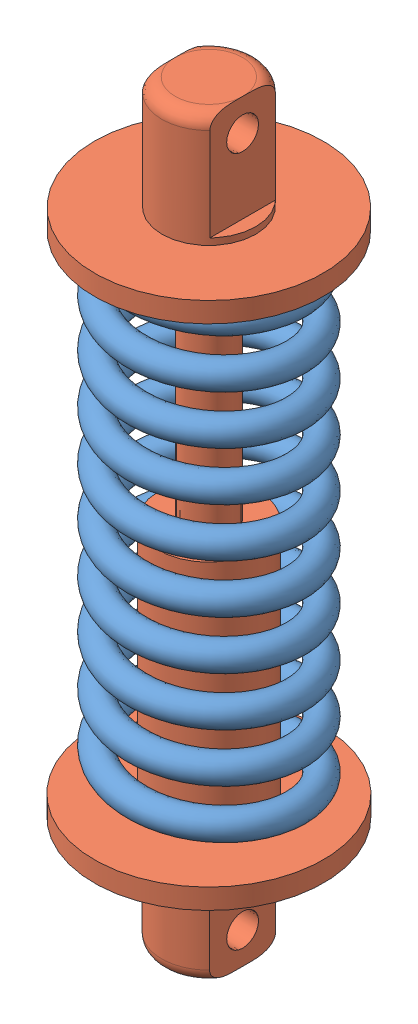
SolidWorks assembly Shock Absorber, configuration Default. Lengths in mm.
Overall size (86.36 285.25 86.36).
2 component instances, 2 part files, 3 mates.
Components (placement in the parent):
- spring-1: spring [Default] at (-42.9952 9.8146 223.0067) size (71.8 203.64 70)
- spring mount-1: spring mount [Default] at (-42.9952 101.6292 223.0067) x (1 0 0) z (0 1 0) size (86.36 86.36 285.25)
Mates (geometry in assembly coordinates):
- Coincident2: coincident anti-aligned: plane of spring-1 through (-42.9952 9.8146 223.0067) normal (0 0 1); plane of spring mount-1 through (-42.9952 101.6292 223.0067) normal (0 0 -1)
- Coincident3: coincident aligned: plane of spring-1 through (-42.9952 9.8146 223.0067) normal (1 0 0); plane of spring mount-1 through (-42.9952 101.6292 223.0067) normal (1 0 0)
- Coincident4: coincident anti-aligned: plane of spring-1 through (-121.87 9.8146 172.2067) normal (0 -1 0); plane of spring mount-1 through (-42.9952 9.8146 179.8267) normal (0 1 0)
